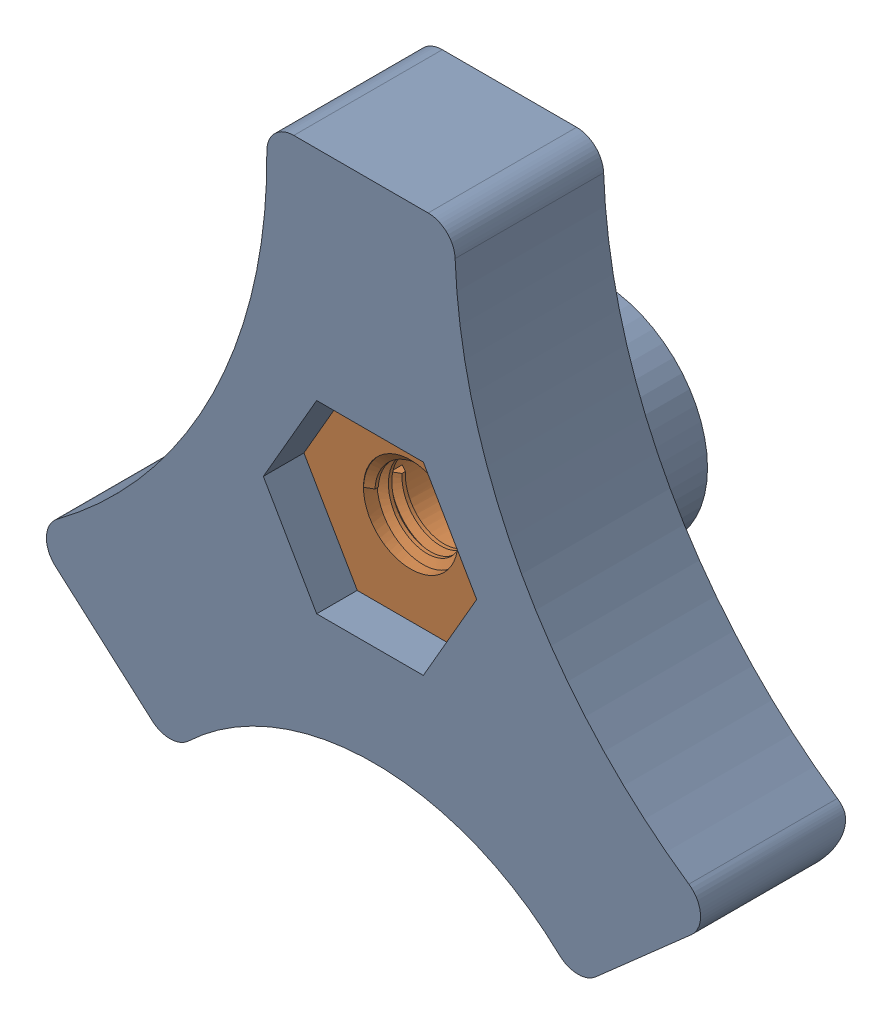
SolidWorks assembly Triangle assembly, configuration Default. Lengths in mm.
Overall size (24.23 21.65 8.5).
2 component instances, 2 part files, 3 mates.
Components (placement in the parent):
- Triangle thing-1: Triangle thing [Default] at origin size (24.23 21.65 8.5)
- bolt fortt-1: bolt fortt [Default] at (0.0073 7.1462 0.5) size (7.91 6.85 3.5)
Mates (geometry in assembly coordinates):
- Coincident5: coincident anti-aligned: plane of Triangle thing-1 through (-1.975 3.7212 0.5) normal (0 1 0); plane of bolt fortt-1 through (-1.9702 3.7212 4) normal (0 -1 0)
- Coincident6: coincident anti-aligned: plane of Triangle thing-1 through (-1.975 10.5628 0.5) normal (0.866025 -0.5 0); plane of bolt fortt-1 through (-1.9702 10.5712 4) normal (-0.866025 0.5 0)
- Coincident7: coincident anti-aligned: plane of Triangle thing-1 through (0 0 0.5) normal (0 0 1); plane of bolt fortt-1 through (0.0073 7.1462 0.5) normal (0 0 -1)
